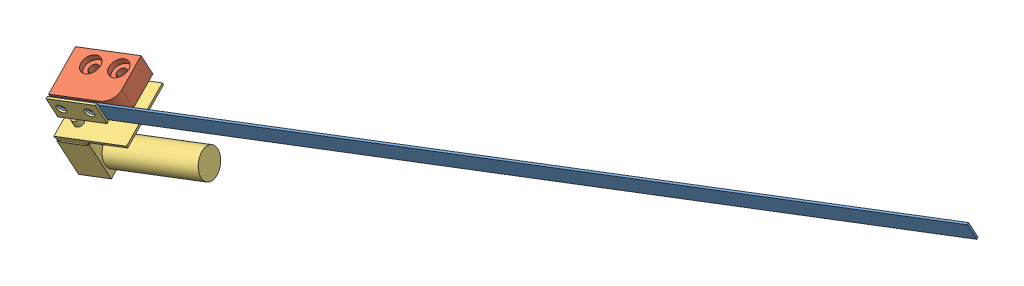
SolidWorks assembly B3_antenna_parts, configuration Default. Lengths in mm.
Overall size (190.05 64.9 41.64).
3 component instances, 3 part files, 6 mates.
Components (placement in the parent):
- Monopole Antenna_17 - コピー-1: Monopole Antenna_17 - コピー [ﾃﾞﾌｫﾙﾄ] at (96.5445 25.6028 16.4245) x (-0.951071 -0.247711 0.184673) z (0.269009 -0.369863 0.889289) size (196 4 0.5)
- B2_antenna fixing parts2-1: B2_antenna fixing parts2 [ﾃﾞﾌｫﾙﾄ] at (-84.5441 -19.7206 46.4497) x (0.951071 0.247711 -0.184673) z (0.269009 -0.369863 0.889289) size (14 5 10.5)
- B3_antenna connector-1: B3_antenna connector [ﾃﾞﾌｫﾙﾄ] at (-86.1125 -28.2252 45.917) x (-0.151983 0.895455 0.418402) z (0.951071 0.247711 -0.184673) size (17.1 14 27.53)
Mates (geometry in assembly coordinates):
- 同心円9: concentric aligned: cylinder of Monopole Antenna_17 - コピー-1 through (-88.4017 -20.4773 52.6431) axis (0.269009 -0.369863 0.889289) radius 1.25; cylinder of B2_antenna fixing parts2-1 through (-88.2671 -20.6623 53.0878) axis (0.269009 -0.369863 0.889289) radius 0.8
- 同心円10: concentric aligned: cylinder of Monopole Antenna_17 - コピー-1 through (-82.6952 -18.9911 51.5351) axis (0.269009 -0.369863 0.889289) radius 1.25; cylinder of B2_antenna fixing parts2-1 through (-82.5607 -19.176 51.9798) axis (0.269009 -0.369863 0.889289) radius 0.8
- 一致8: coincident anti-aligned: plane of Monopole Antenna_17 - コピー-1 through (95.9366 29.1846 18.0981) normal (-0.269009 0.369863 -0.889289); plane of B2_antenna fixing parts2-1 through (-90.5492 -18.919 54.5031) normal (0.269009 -0.369863 0.889289)
- 同心円17: concentric anti-aligned: cylinder of Monopole Antenna_17 - コピー-1 through (-88.4017 -20.4773 52.6431) axis (0.269009 -0.369863 0.889289) radius 1.25; cylinder of B3_antenna connector-1 through (-87.7022 -21.439 54.9553) axis (-0.269009 0.369863 -0.889289) radius 1.05
- 同心円18: concentric anti-aligned: cylinder of Monopole Antenna_17 - コピー-1 through (-82.6952 -18.9911 51.5351) axis (0.269009 -0.369863 0.889289) radius 1.25; cylinder of B3_antenna connector-1 through (-81.9958 -19.9527 53.8473) axis (-0.269009 0.369863 -0.889289) radius 1.05
- 一致9: coincident anti-aligned: plane of Monopole Antenna_17 - コピー-1 through (96.0711 28.9996 18.5427) normal (0.269009 -0.369863 0.889289); plane of B3_antenna connector-1 through (-80.4 -16.4956 53.0032) normal (-0.269009 0.369863 -0.889289)
